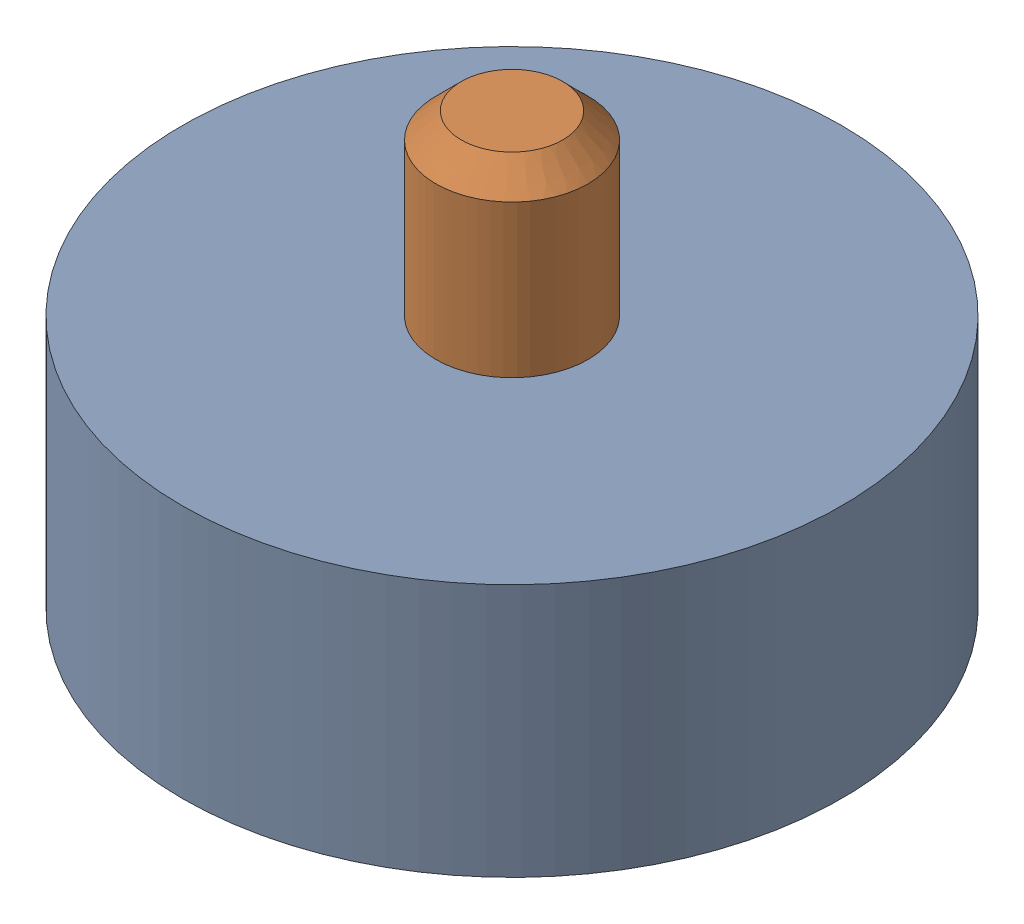
SolidWorks assembly Bearing-13x5x3mm+Pin-12mm, configuration Default. Lengths in mm.
Overall size (13 12 13).
2 component instances, 2 part files, 2 mates.
Components (placement in the parent):
- Bearing-13x5x3mm-1: Bearing-13x5x3mm [Default] at (-2.7507 2.859 10.3738) size (13 5 13)
- Pin-12mm-1: Pin-12mm [Default] at (-2.7507 11.359 10.3738) x (1 0 0) z (0 -1 0) size (3 3 12)
Mates (geometry in assembly coordinates):
- Concentric1: concentric anti-aligned: cylinder of Bearing-13x5x3mm-1 through (-2.7507 7.859 10.3738) axis (0 -1 0) radius 1.5; cylinder of Pin-12mm-1 through (-2.7507 -0.641 10.3738) axis (0 1 0) radius 1.5
- Width1: width anti-aligned: plane of Pin-12mm-1 through (-2.7507 11.359 10.3738) normal (0 1 0); plane of Bearing-13x5x3mm-1 through (-2.7507 -0.641 10.3738) normal (0 -1 0); plane of Pin-12mm-1 through (-2.7507 2.859 10.3738) normal (0 -1 0); plane of Bearing-13x5x3mm-1 through (-2.7507 7.859 10.3738) normal (0 1 0)
